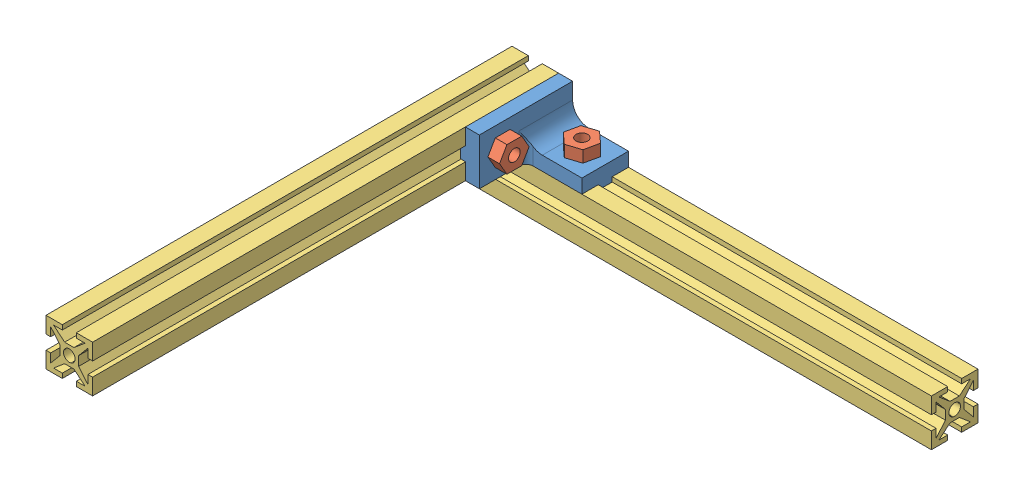
SolidWorks assembly Bracket_L20x15_CrossWithNuts, configuration Default. Lengths in mm.
Overall size (100 20 100).
5 component instances, 3 part files, 12 mates.
Components (placement in the parent):
- Bracket_L20x15_Cross-1: Bracket_L20x15_Cross [Default] at (-71.8769 13.7148 21.8598) size (16 11 20)
- Nut3mm-2: Nut3mm [Default] at (-66.3769 18.7148 36.8598) x (0 0 1) z (-1 0 0) size (6.35 5.5 2.5)
- Nut3mm-3: Nut3mm [Default] at (-61.8769 19.2148 26.8598) x (0.740459 0 0.672102) z (0 -1 0) size (6.35 5.5 2.5)
- Makerbeam50-1000mm-1: Makerbeam50-1000mm [100mm] at (-76.8769 18.7148 21.8598) size (10 10 100)
- Makerbeam50-1000mm-2: Makerbeam50-1000mm [100mm] at (-81.8769 8.7148 26.8598) x (0 0 1) z (1 0 0) size (10 10 100)
Mates (geometry in assembly coordinates):
- Coaxiale1: concentric anti-aligned: cylinder of Bracket_L20x15_Cross-1 through (-56.8769 18.7148 16.8598) axis (-1 0 0) radius 1.5; cylinder of ? through (-68.8769 18.7148 16.8598) axis (1 0 0) radius 1.25
- Coaxiale2: concentric anti-aligned: cylinder of Bracket_L20x15_Cross-1 through (-56.8769 18.7148 36.8598) axis (-1 0 0) radius 1.6; cylinder of Nut3mm-2 through (-68.8769 18.7148 36.8598) axis (1 0 0) radius 1.25
- Coïncidente1: coincident anti-aligned: plane of Bracket_L20x15_Cross-1 through (-68.8769 20.2148 41.8598) normal (1 0 0); plane of Nut3mm-2 through (-68.8769 18.7148 36.8598) normal (-1 0 0)
- Coïncidente2: coincident anti-aligned: plane of Bracket_L20x15_Cross-1 through (-68.8769 20.7148 36.8598) normal (1 0 0); plane of ? through (-68.8769 18.7148 16.8598) normal (-1 0 0)
- Coaxiale3: concentric anti-aligned: cylinder of Bracket_L20x15_Cross-1 through (-61.8769 23.7148 26.8598) axis (0 -1 0) radius 1.6; cylinder of Nut3mm-3 through (-61.8769 16.7148 26.8598) axis (0 1 0) radius 1.25
- Coïncidente3: coincident anti-aligned: plane of Bracket_L20x15_Cross-1 through (-56.8769 16.7148 41.8598) normal (0 1 0); plane of Nut3mm-3 through (-61.8769 16.7148 26.8598) normal (0 -1 0)
- Coïncidente4: coincident anti-aligned: plane of Bracket_L20x15_Cross-1 through (-71.8769 23.7148 41.8598) normal (-1 0 0); plane of Makerbeam50-1000mm-1 through (-71.8769 17.2148 121.8598) normal (1 0 0)
- Coïncidente5: coincident aligned: plane of Bracket_L20x15_Cross-1 through (-65.3769 20.2148 21.8598) normal (0 0 -1); plane of Makerbeam50-1000mm-1 through (-76.8769 18.7148 21.8598) normal (0 0 -1)
- Coïncidente6: coincident aligned: plane of Bracket_L20x15_Cross-1 through (-71.8769 13.7148 41.8598) normal (0 -1 0); plane of Makerbeam50-1000mm-1 through (-75.3769 13.7148 121.8598) normal (0 -1 0)
- Coïncidente7: coincident anti-aligned: plane of Bracket_L20x15_Cross-1 through (-71.8769 13.7148 41.8598) normal (0 -1 0); plane of Makerbeam50-1000mm-2 through (18.1231 13.7148 28.3598) normal (0 1 0)
- Coïncidente8: coincident aligned: plane of Bracket_L20x15_Cross-1 through (-65.3769 20.2148 21.8598) normal (0 0 -1); plane of Makerbeam50-1000mm-2 through (18.1231 13.7148 21.8598) normal (0 0 -1)
- Coïncidente9: coincident aligned: plane of Makerbeam50-1000mm-1 through (-81.8769 13.7148 121.8598) normal (-1 0 0); plane of Makerbeam50-1000mm-2 through (-81.8769 8.7148 26.8598) normal (-1 0 0)
